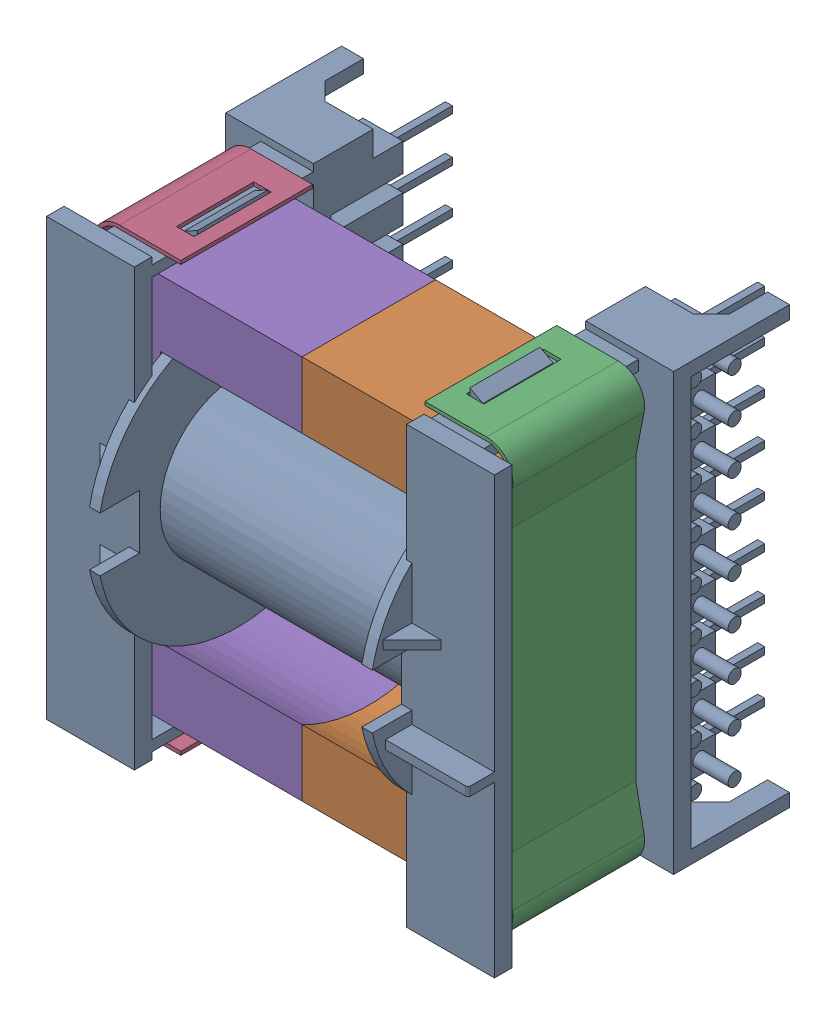
SolidWorks assembly L2, configuration Default. Lengths in mm.
Overall size (51 49.6 42.6).
6 component instances, 5 part files, 0 mates.
Components (placement in the parent):
- User_Library-ETD44_NO_AIRGAP-1: User_Library-ETD44_NO_AIRGAP [Default] at (113.2599 101.8636 0) x (0 1 0) z (0 0 1) size (49.6 51 42.6)
  - User_Library-ETD44_NO_AIRGAP_CoilFormerETD44-1: User_Library-ETD44_NO_AIRGAP_CoilFormerETD44 [Default] at origin size (49.6 51 42.6)
  - User_Library-ETD44_NO_AIRGAP_ETD44_core1-1: User_Library-ETD44_NO_AIRGAP_ETD44_core1 [Default] at origin size (43.8 22.5 15.2)
  - User_Library-ETD44_NO_AIRGAP_ClipETD44_2-1: User_Library-ETD44_NO_AIRGAP_ClipETD44_2 [Default] at origin size (48.8 10 15)
  - User_Library-ETD44_NO_AIRGAP_ClipETD44_1-1: User_Library-ETD44_NO_AIRGAP_ClipETD44_1 [Default] at origin size (48.8 10 15)
  - User_Library-ETD44_NO_AIRGAP_ETD44_core2-1: User_Library-ETD44_NO_AIRGAP_ETD44_core2 [Default] at origin size (43.8 22.5 15.2)
